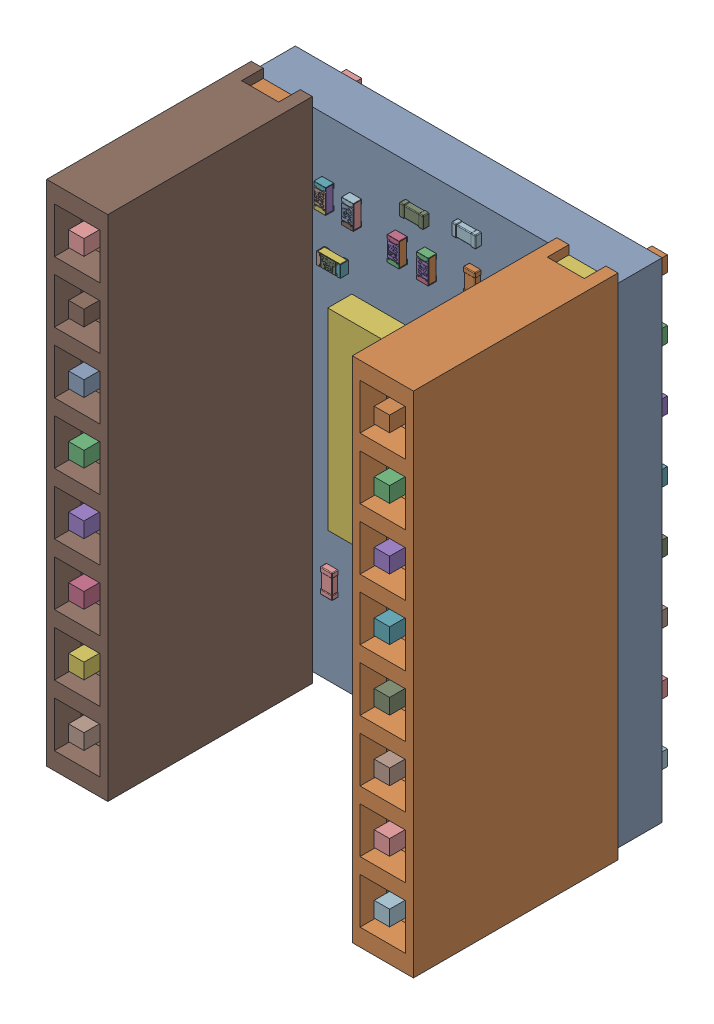
SolidWorks assembly PCB-2, configuration ﾃﾞﾌｫﾙﾄ. Lengths in mm.
Overall size (15.24 21.12 11.54).
81 component instances, 15 part files, 0 mates.
Components (placement in the parent):
- Board-2-1: Board-2 [ﾃﾞﾌｫﾙﾄ] at origin size (15.24 20.32 1.83)
  - Open CASCADE STEP translator 6.8 2.1.1-1: Open CASCADE STEP translator 6.8 2.1.1 [ﾃﾞﾌｫﾙﾄ] at (0 0 -1.8339) size (15.24 20.32 1.83)
- X-1: X [ﾃﾞﾌｫﾙﾄ] at origin size (15.24 21.12 11.5)
  - DS1023-1x8SF11-1: DS1023-1x8SF11 [ﾃﾞﾌｫﾙﾄ] at (13.9593 19.0061 0) x (0 -1 0) z (0 0 1) size (21.12 2.54 11.5)
  - DS1023-1x8SF11-2: DS1023-1x8SF11 [ﾃﾞﾌｫﾙﾄ] at (1.2593 19.0061 0) x (0 -1 0) z (0 0 1) size (21.12 2.54 11.5)
- U5-1: U5 [ﾃﾞﾌｫﾙﾄ] at origin size (3.17 3.19 0.82)
  - 6641442208-1: 6641442208 [ﾃﾞﾌｫﾙﾄ] at (8.4975 4.6 -2.7339) size (3.17 3.19 0.81)
    - Extruded-19-1: Extruded-19 [ﾃﾞﾌｫﾙﾄ] at origin size (3.17 3.19 0.81)
  - 6641441808-1: 6641441808 [ﾃﾞﾌｫﾙﾄ] at (7.1852 5.8608 -2.7339) x (0 -1 0) z (0 0 -1) size (0.2 0.2 0.01)
    - Cylinder-20-1: Cylinder-20 [ﾃﾞﾌｫﾙﾄ] at origin size (0.2 0.2 0.01)
- U1-1: U1 [ﾃﾞﾌｫﾙﾄ] at origin size (3.19 3.17 0.82)
  - 6641441568-1: 6641441568 [ﾃﾞﾌｫﾙﾄ] at (6.25 17.0875 -2.7339) size (3.19 3.17 0.81)
    - Extruded-21-1: Extruded-21 [ﾃﾞﾌｫﾙﾄ] at origin size (3.19 3.17 0.81)
  - 6641441328-1: 6641441328 [ﾃﾞﾌｫﾙﾄ] at (7.5108 18.3998 -2.7339) x (-1 0 0) z (0 0 -1) size (0.2 0.2 0.01)
    - Cylinder-22-1: Cylinder-22 [ﾃﾞﾌｫﾙﾄ] at origin size (0.2 0.2 0.01)
- C8-1: C8 [ﾃﾞﾌｫﾙﾄ] at origin size (0.5 1 0.5)
  - User_Library-C0402-1-1: User_Library-C0402-1 [ﾃﾞﾌｫﾙﾄ] at (11.385 3.6234 -1.8339) x (0 -1 0) z (0 0 -1) size (1 0.5 0.5)
- R9-1: R9 [ﾃﾞﾌｫﾙﾄ] at origin size (0.5 1 0.35)
  - User_Library-User_Library-RES0402-2-1: User_Library-User_Library-RES0402-2 [ﾃﾞﾌｫﾙﾄ] at (3.9988 13.3623 -1.8339) x (0 1 0) z (0 0 -1) size (1 0.5 0.35)
- R1-1: R1 [ﾃﾞﾌｫﾙﾄ] at origin size (0.5 1 0.35)
  - User_Library-User_Library-RES0402-2-1: User_Library-User_Library-RES0402-2 [ﾃﾞﾌｫﾙﾄ] at (3.1812 17.5123 0) x (0 1 0) z (0 0 1) size (1 0.5 0.35)
- C3-1: C3 [ﾃﾞﾌｫﾙﾄ] at origin size (0.5 1 0.5)
  - User_Library-C0402-1-1: User_Library-C0402-1 [ﾃﾞﾌｫﾙﾄ] at (11.895 11.6466 -1.8339) x (0 1 0) z (0 0 -1) size (1 0.5 0.5)
- U4-1: U4 [ﾃﾞﾌｫﾙﾄ] at origin size (3.17 3.19 0.82)
  - 6641442208-1: 6641442208 [ﾃﾞﾌｫﾙﾄ] at (4.4325 4.57 -2.7339) size (3.17 3.19 0.81)
    - Extruded-19-1: Extruded-19 [ﾃﾞﾌｫﾙﾄ] at origin size (3.17 3.19 0.81)
  - 6641440128-1: 6641440128 [ﾃﾞﾌｫﾙﾄ] at (5.7448 3.3092 -2.7339) x (0 1 0) z (0 0 -1) size (0.2 0.2 0.01)
    - Cylinder-23-1: Cylinder-23 [ﾃﾞﾌｫﾙﾄ] at origin size (0.2 0.2 0.01)
- U3-1: U3 [ﾃﾞﾌｫﾙﾄ] at origin size (3.19 3.17 0.82)
  - 6641441328-1: 6641441328 [ﾃﾞﾌｫﾙﾄ] at (12.1608 18.3998 -2.7339) x (-1 0 0) z (0 0 -1) size (0.2 0.2 0.01)
    - Cylinder-22-1: Cylinder-22 [ﾃﾞﾌｫﾙﾄ] at origin size (0.2 0.2 0.01)
  - 6641441568-1: 6641441568 [ﾃﾞﾌｫﾙﾄ] at (10.9 17.0875 -2.7339) size (3.19 3.17 0.81)
    - Extruded-21-1: Extruded-21 [ﾃﾞﾌｫﾙﾄ] at origin size (3.19 3.17 0.81)
- C1-1: C1 [ﾃﾞﾌｫﾙﾄ] at origin size (0.5 1 0.5)
  - User_Library-C0402-1-1: User_Library-C0402-1 [ﾃﾞﾌｫﾙﾄ] at (9.535 17.4466 0) x (0 1 0) z (0 0 1) size (1 0.5 0.5)
- C2-1: C2 [ﾃﾞﾌｫﾙﾄ] at origin size (1 0.5 0.5)
  - User_Library-C0402-1-1: User_Library-C0402-1 [ﾃﾞﾌｫﾙﾄ] at (10.4533 16.155 0) x (-1 0 0) z (0 0 1) size (1 0.5 0.5)
- C4-1: C4 [ﾃﾞﾌｫﾙﾄ] at origin size (1 0.5 0.5)
  - User_Library-C0402-1-1: User_Library-C0402-1 [ﾃﾞﾌｫﾙﾄ] at (7.7766 4.515 0) x (1 0 0) z (0 0 1) size (1 0.5 0.5)
- C5-1: C5 [ﾃﾞﾌｫﾙﾄ] at origin size (1 0.5 0.5)
  - User_Library-C0402-1-1: User_Library-C0402-1 [ﾃﾞﾌｫﾙﾄ] at (11.2534 3.655 0) x (-1 0 0) z (0 0 1) size (1 0.5 0.5)
- C7-1: C7 [ﾃﾞﾌｫﾙﾄ] at origin size (0.81 1.6 0.8)
  - 6641443168-1: 6641443168 [ﾃﾞﾌｫﾙﾄ] at (12.3314 3.3249 -2.6339) size (0.8 0.23 0.8)
    - Extruded-24-1: Extruded-24 [ﾃﾞﾌｫﾙﾄ] at origin size (0.8 0.23 0.8)
  - 6641443168-2: 6641443168 [ﾃﾞﾌｫﾙﾄ] at (12.3314 4.6949 -2.6339) size (0.8 0.23 0.8)
    - Extruded-24-1: Extruded-24 [ﾃﾞﾌｫﾙﾄ] at origin size (0.8 0.23 0.8)
  - 6641442768-1: 6641442768 [ﾃﾞﾌｫﾙﾄ] at (12.3313 4.0099 -2.6339) size (0.8 1.14 0.8)
    - Extruded-25-1: Extruded-25 [ﾃﾞﾌｫﾙﾄ] at origin size (0.8 1.14 0.8)
- C11-1: C11 [ﾃﾞﾌｫﾙﾄ] at origin size (1 0.5 0.5)
  - User_Library-C0402-1-1: User_Library-C0402-1 [ﾃﾞﾌｫﾙﾄ] at (6.8766 18.415 0) x (1 0 0) z (0 0 1) size (1 0.5 0.5)
- C12-1: C12 [ﾃﾞﾌｫﾙﾄ] at origin size (0.5 1 0.5)
  - User_Library-C0402-1-1: User_Library-C0402-1 [ﾃﾞﾌｫﾙﾄ] at (3.095 3.6734 0) x (0 -1 0) z (0 0 1) size (1 0.5 0.5)
- C13-1: C13 [ﾃﾞﾌｫﾙﾄ] at origin size (0.5 1 0.5)
  - User_Library-C0402-1-1: User_Library-C0402-1 [ﾃﾞﾌｫﾙﾄ] at (4.235 11.2234 -1.8339) x (0 -1 0) z (0 0 -1) size (1 0.5 0.5)
- C14-1: C14 [ﾃﾞﾌｫﾙﾄ] at origin size (0.5 1 0.5)
  - User_Library-C0402-1-1: User_Library-C0402-1 [ﾃﾞﾌｫﾙﾄ] at (11.895 9.1466 -1.8339) x (0 1 0) z (0 0 -1) size (1 0.5 0.5)
- C15-1: C15 [ﾃﾞﾌｫﾙﾄ] at origin size (0.5 1 0.5)
  - User_Library-C0402-1-1: User_Library-C0402-1 [ﾃﾞﾌｫﾙﾄ] at (12.485 4.8966 0) x (0 1 0) z (0 0 1) size (1 0.5 0.5)
- J3-1: J3 [ﾃﾞﾌｫﾙﾄ] at origin size (2.54 20.32 11.54)
  - 1001-8-1: 1001-8 [ﾃﾞﾌｫﾙﾄ] at (1.259 19.037 0) x (0 -1 0) z (0 0 1) size (20.32 2.54 11.54)
- J4-1: J4 [ﾃﾞﾌｫﾙﾄ] at origin size (2.54 20.32 11.54)
  - 1001-8-1: 1001-8 [ﾃﾞﾌｫﾙﾄ] at (13.959 19.037 0) x (0 -1 0) z (0 0 1) size (20.32 2.54 11.54)
- R2-1: R2 [ﾃﾞﾌｫﾙﾄ] at origin size (1.25 2 0.5)
  - User_Library-R_0805-1: User_Library-R_0805 [ﾃﾞﾌｫﾙﾄ] at (3.19 17.0633 -1.8239) x (0 1 0) z (0 0 -1) size (2 1.25 0.5)
- R3-1: R3 [ﾃﾞﾌｫﾙﾄ] at origin size (0.5 1 0.35)
  - User_Library-User_Library-RES0402-2-1: User_Library-User_Library-RES0402-2 [ﾃﾞﾌｫﾙﾄ] at (7.4488 17.1077 0) x (0 -1 0) z (0 0 1) size (1 0.5 0.35)
- R4-1: R4 [ﾃﾞﾌｫﾙﾄ] at origin size (1 0.5 0.35)
  - User_Library-User_Library-RES0402-2-1: User_Library-User_Library-RES0402-2 [ﾃﾞﾌｫﾙﾄ] at (3.5377 15.3012 0) x (-1 0 0) z (0 0 1) size (1 0.5 0.35)
- R6-1: R6 [ﾃﾞﾌｫﾙﾄ] at origin size (0.5 1 0.35)
  - User_Library-User_Library-RES0402-2-1: User_Library-User_Library-RES0402-2 [ﾃﾞﾌｫﾙﾄ] at (4.3312 17.5123 0) x (0 1 0) z (0 0 1) size (1 0.5 0.35)
- R8-1: R8 [ﾃﾞﾌｫﾙﾄ] at origin size (0.5 1 0.35)
  - User_Library-User_Library-RES0402-2-1: User_Library-User_Library-RES0402-2 [ﾃﾞﾌｫﾙﾄ] at (6.2312 17.1123 0) x (0 1 0) z (0 0 1) size (1 0.5 0.35)
- U2-1: U2 [ﾃﾞﾌｫﾙﾄ] at origin size (8 8 1)
  - 6641437328-1: 6641437328 [ﾃﾞﾌｫﾙﾄ] at (8.169 10.388 0) size (8 8 1)
    - Extruded-26-1: Extruded-26 [ﾃﾞﾌｫﾙﾄ] at origin size (8 8 1)
  - 6641437008-1: 6641437008 [ﾃﾞﾌｫﾙﾄ] at (11.439 13.736 0) x (0 -1 0) z (0 0 1) size (0.4 0.4 1)
    - Cylinder-27-1: Cylinder-27 [ﾃﾞﾌｫﾙﾄ] at origin size (0.4 0.4 1)
- R7-1: R7 [ﾃﾞﾌｫﾙﾄ] at origin size (1.25 2 0.5)
  - User_Library-R_0805-1: User_Library-R_0805 [ﾃﾞﾌｫﾙﾄ] at (3.74 8.4067 -1.8239) x (0 -1 0) z (0 0 -1) size (2 1.25 0.5)
- C10-1: C10 [ﾃﾞﾌｫﾙﾄ] at origin size (1 0.5 0.5)
  - User_Library-C0402-1-1: User_Library-C0402-1 [ﾃﾞﾌｫﾙﾄ] at (9.0534 19.305 0) x (-1 0 0) z (0 0 1) size (1 0.5 0.5)
